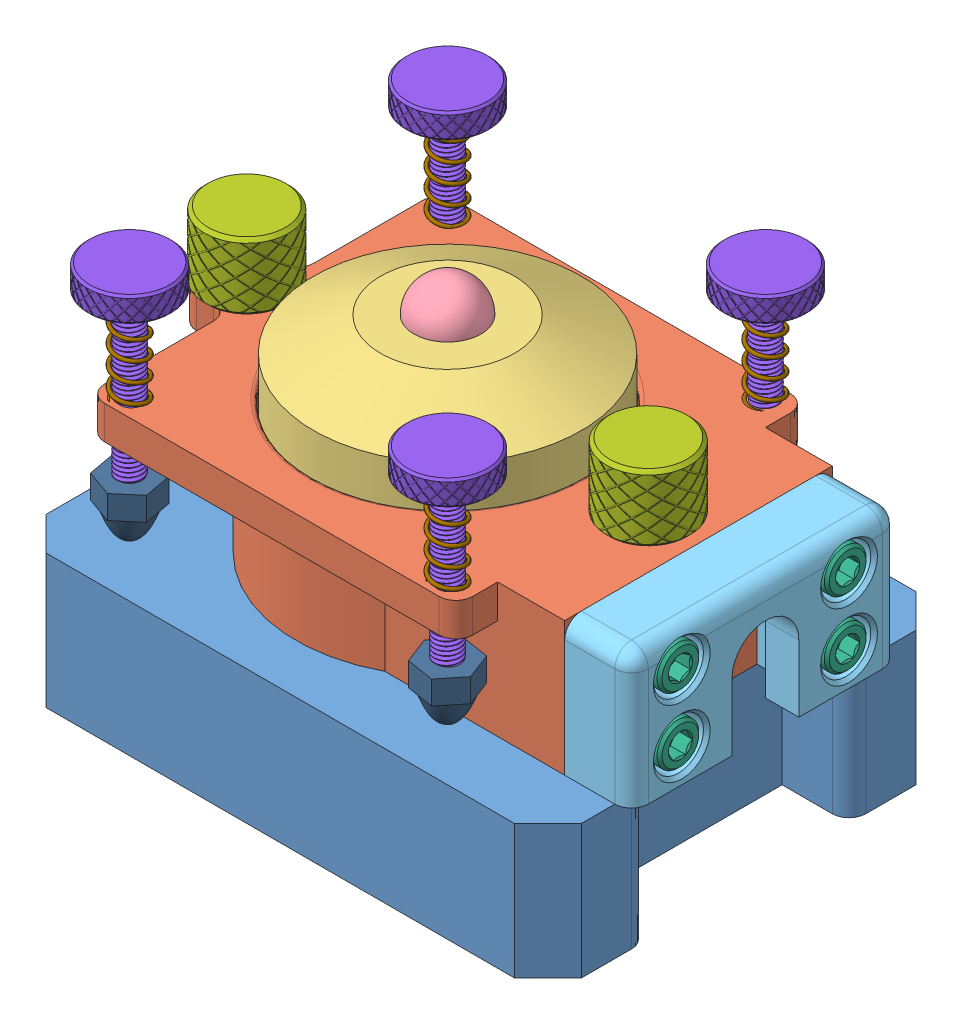
SolidWorks assembly 2in_shear_box_assy, configuration Default. Lengths in mm.
Overall size (109.63 73.24 82.73).
23 component instances, 10 part files, 48 mates.
Components (placement in the parent):
- 2in_shear_box_base-1: 2in_shear_box_base [Default] at origin size (101.6 25.4 76.2)
- 2in_sample_top_plate-1: 2in_sample_top_plate [Default] at (-6.35 25.4 0) x (0 0 -1) z (1 0 0) size (66.67 25.4 92.08)
- normal_puck-1: normal_puck [Default] at (-6.35 39.1613 0) x (0.605714 0 0.795683) z (-0.795683 0 0.605714) size (50.8 25.4 50.8)
- 0.5in_ball_bearing-1: 0.5in_ball_bearing [Default] at (-6.35 64.5613 0) size (12.7 12.7 12.7)
- retainer_plate-1: retainer_plate [Default] at (53.975 38.1 0) x (0 0 -1) z (1 0 0) size (50.8 25.4 12.7)
- 91251A245-1: 91251A245 [91251A245] at (29.845 31.75 -15.875) x (0 -0.48022 0.877148) z (-1 0 0) size (7.92 7.92 25.03)
- 91251A245-2: 91251A245 [91251A245] at (29.845 44.45 -15.875) x (0 0.550718 -0.834691) z (-1 0 0) size (7.92 7.92 25.03)
- 91251A245-3: 91251A245 [91251A245] at (29.845 31.75 15.875) x (0 0.998249 -0.059147) z (-1 0 0) size (7.92 7.92 25.03)
- 91251A245-4: 91251A245 [91251A245] at (29.845 44.45 15.875) x (0 -0.030227 -0.999543) z (-1 0 0) size (7.92 7.92 25.03)
- 93585A194-1: 93585A194 [93585A194] at (-44.45 50.8 0) x (0.658739 0 -0.752371) z (0 1 0) size (15.88 15.88 44.99)
- 93585A194-2: 93585A194 [93585A194] at (31.75 50.8 0) x (0.99977 0 0.021452) z (0 1 0) size (15.88 15.88 44.99)
- 91746A378-1: 91746A378 [91746A378] at (-36.5125 68.4784 -30.1625) x (0.840552 0 0.54173) z (0 1 0) size (15.88 15.88 43.31)
- 91746A378-2: 91746A378 [91746A378] at (23.8125 68.4784 -30.1625) x (0.723397 0 0.690432) z (0 1 0) size (15.88 15.88 43.31)
- 91746A378-3: 91746A378 [91746A378] at (-36.5125 68.4784 30.1625) x (0.343254 0 -0.939242) z (0 1 0) size (15.88 15.88 43.31)
- 91746A378-4: 91746A378 [91746A378] at (23.8125 68.4784 30.1625) x (0.645785 0 -0.763519) z (0 1 0) size (15.88 15.88 43.31)
- 9657K285-1: 9657K285 [9657K285] at (-36.5125 50.1142 -30.1625) x (0.840552 0 0.54173) z (0 -1 0) size (6.55 6.65 19.38)
- 9657K285-2: 9657K285 [9657K285] at (23.8125 50.1142 -30.1625) x (-0.723397 0 -0.690432) z (0 -1 0) size (6.55 6.65 19.38)
- 9657K285-3: 9657K285 [9657K285] at (-36.5125 50.1142 30.1625) x (0.343254 0 -0.939242) z (0 -1 0) size (6.55 6.65 19.38)
- 9657K285-4: 9657K285 [9657K285] at (23.8125 50.1142 30.1625) x (0.645785 0 -0.763519) z (0 -1 0) size (6.55 6.65 19.38)
- nylon_10_32_cap-1: nylon_10_32_cap [Default] at (23.8125 38.2524 -30.1625) x (-0.932261 0 -0.361786) z (-0.361786 0 0.932261) size (10.53 10.32 9.45)
- nylon_10_32_cap-2: nylon_10_32_cap [Default] at (-36.5125 38.2524 30.1625) x (0.78666 0 -0.617387) z (-0.617387 0 -0.78666) size (10.53 10.32 9.45)
- nylon_10_32_cap-3: nylon_10_32_cap [Default] at (23.8125 38.2524 30.1625) x (0.658929 0 -0.752206) z (-0.752206 0 -0.658929) size (10.53 10.32 9.45)
- nylon_10_32_cap-4: nylon_10_32_cap [Default] at (-36.5125 38.2524 -30.1625) x (-0.105492 0 -0.99442) z (-0.99442 0 0.105492) size (10.53 10.32 9.45)
Mates (geometry in assembly coordinates):
- Concentric3: concentric aligned: cylinder of 2in_shear_box_base-1 through (-6.35 12.7 0) axis (0 1 0) radius 25.5905; cylinder of 2in_sample_top_plate-1 through (-6.35 25.4 0) axis (0 1 0) radius 25.5905
- Coincident3: coincident anti-aligned: plane of 2in_shear_box_base-1 through (0 25.4 0) normal (0 1 0); plane of 2in_sample_top_plate-1 through (-6.35 25.4 0) normal (0 -1 0)
- Concentric4: concentric anti-aligned: cylinder of 2in_sample_top_plate-1 through (-6.35 25.4 0) axis (0 1 0) radius 25.5905; cylinder of normal_puck-1 through (-6.35 39.1613 0) axis (0 -1 0) radius 25.4
- Concentric5: concentric: sphere of normal_puck-1; sphere of 0.5in_ball_bearing-1
- Coincident5: coincident anti-aligned: plane of 2in_sample_top_plate-1 through (41.275 25.4 0) normal (1 0 0); plane of retainer_plate-1 through (41.275 38.1 0) normal (-1 0 0)
- Coincident6: coincident aligned: line of 2in_sample_top_plate-1 through (41.275 50.8 -25.4) axis (0 0 1); line of retainer_plate-1 through (41.275 50.8 -22.225) axis (0 0 1)
- Coincident7: coincident aligned: line of 2in_sample_top_plate-1 through (41.275 50.8 25.4) axis (0 -1 0); line of retainer_plate-1 through (41.275 47.625 25.4) axis (0 -1 0)
- Concentric6: concentric aligned: circle of 2in_sample_top_plate-1; circle of 93585A194-1
- Coincident9: coincident anti-aligned: plane of 2in_sample_top_plate-1 through (3.175 50.8 -25.4) normal (0 1 0); plane of 93585A194-1 through (-44.45 50.8 0) normal (0 -1 0)
- Concentric7: concentric aligned: circle of 2in_sample_top_plate-1; circle of 93585A194-2
- Coincident10: coincident anti-aligned: plane of 2in_sample_top_plate-1 through (3.175 50.8 -25.4) normal (0 1 0); plane of 93585A194-2 through (31.75 50.8 0) normal (0 -1 0)
- Concentric9: concentric aligned: circle of retainer_plate-1; circle of 91251A245-2
- Coincident11: coincident anti-aligned: plane of retainer_plate-1 through (48.895 44.45 -20.6375) normal (1 0 0); plane of 91251A245-2 through (48.895 44.45 -15.875) normal (-1 0 0)
- Concentric10: concentric aligned: circle of retainer_plate-1; circle of 91251A245-1
- Coincident12: coincident anti-aligned: plane of retainer_plate-1 through (48.895 31.75 -20.6375) normal (1 0 0); plane of 91251A245-1 through (48.895 31.75 -15.875) normal (-1 0 0)
- Concentric11: concentric aligned: circle of retainer_plate-1; circle of 91251A245-4
- Coincident13: coincident anti-aligned: plane of retainer_plate-1 through (48.895 44.45 11.1125) normal (1 0 0); plane of 91251A245-4 through (48.895 44.45 15.875) normal (-1 0 0)
- Concentric12: concentric aligned: circle of retainer_plate-1; circle of 91251A245-3
- Coincident14: coincident anti-aligned: plane of retainer_plate-1 through (48.895 31.75 11.1125) normal (1 0 0); plane of 91251A245-3 through (48.895 31.75 15.875) normal (-1 0 0)
- Concentric13: concentric aligned: circle of 2in_sample_top_plate-1; circle of 91746A378-1
- Concentric14: concentric aligned: circle of 2in_sample_top_plate-1; circle of 91746A378-2
- Concentric15: concentric aligned: circle of 2in_sample_top_plate-1; circle of 91746A378-4
- Concentric16: concentric aligned: circle of 2in_sample_top_plate-1; circle of 91746A378-3
- Parallel2: parallel aligned: plane of 2in_shear_box_base-1 through (-50.8 25.4 -38.1) normal (0 0 -1); plane of 2in_sample_top_plate-1 through (3.175 25.4 -25.4) normal (0 0 -1)
- Coincident18: coincident anti-aligned: plane of 2in_sample_top_plate-1 through (3.175 50.8 -25.4) normal (0 1 0); plane of 9657K285-2
- Coincident19: coincident aligned: plane of 91746A378-2 through (23.8125 68.4784 -30.1625) normal (0 -1 0); plane of 9657K285-2
- Coincident20: coincident aligned: plane of 91746A378-2; plane of 9657K285-2
- Coincident21: coincident anti-aligned: plane of 91746A378-2; plane of 9657K285-2
- Coincident24: coincident anti-aligned: plane of 2in_sample_top_plate-1 through (3.175 50.8 -25.4) normal (0 1 0); plane of 9657K285-1
- Coincident25: coincident aligned: plane of 91746A378-1 through (-36.5125 68.4784 -30.1625) normal (0 -1 0); plane of 9657K285-1
- Coincident26: coincident anti-aligned: plane of 91746A378-1; plane of 9657K285-1
- Coincident27: coincident aligned: plane of 91746A378-1; plane of 9657K285-1
- Coincident28: coincident anti-aligned: plane of 2in_sample_top_plate-1 through (3.175 50.8 -25.4) normal (0 1 0); plane of 9657K285-4
- Coincident29: coincident aligned: plane of 91746A378-4 through (23.8125 68.4784 30.1625) normal (0 -1 0); plane of 9657K285-4
- Coincident30: coincident anti-aligned: plane of 91746A378-4; plane of 9657K285-4
- Coincident31: coincident aligned: plane of 91746A378-4; plane of 9657K285-4
- Coincident32: coincident anti-aligned: plane of 2in_sample_top_plate-1 through (3.175 50.8 -25.4) normal (0 1 0); plane of 9657K285-3
- Coincident33: coincident aligned: plane of 91746A378-3 through (-36.5125 68.4784 30.1625) normal (0 -1 0); plane of 9657K285-3
- Coincident34: coincident anti-aligned: plane of 91746A378-3; plane of 9657K285-3
- Coincident35: coincident aligned: plane of 91746A378-3; plane of 9657K285-3
- Coincident38: coincident anti-aligned: plane of 91746A378-4 through (23.8125 30.3784 30.1625) normal (0 -1 0); circle of nylon_10_32_cap-3
- Concentric19: concentric aligned: circle of 91746A378-4; circle of nylon_10_32_cap-3
- Coincident39: coincident anti-aligned: plane of 91746A378-3 through (-36.5125 30.3784 30.1625) normal (0 -1 0); circle of nylon_10_32_cap-2
- Concentric22: concentric aligned: circle of 91746A378-3; circle of nylon_10_32_cap-2
- Coincident40: coincident anti-aligned: plane of 91746A378-2 through (23.8125 30.3784 -30.1625) normal (0 -1 0); circle of nylon_10_32_cap-1
- Concentric23: concentric aligned: circle of 91746A378-2; circle of nylon_10_32_cap-1
- Coincident41: coincident anti-aligned: plane of 91746A378-1 through (-36.5125 30.3784 -30.1625) normal (0 -1 0); circle of nylon_10_32_cap-4
- Concentric25: concentric aligned: circle of 91746A378-1; circle of nylon_10_32_cap-4
